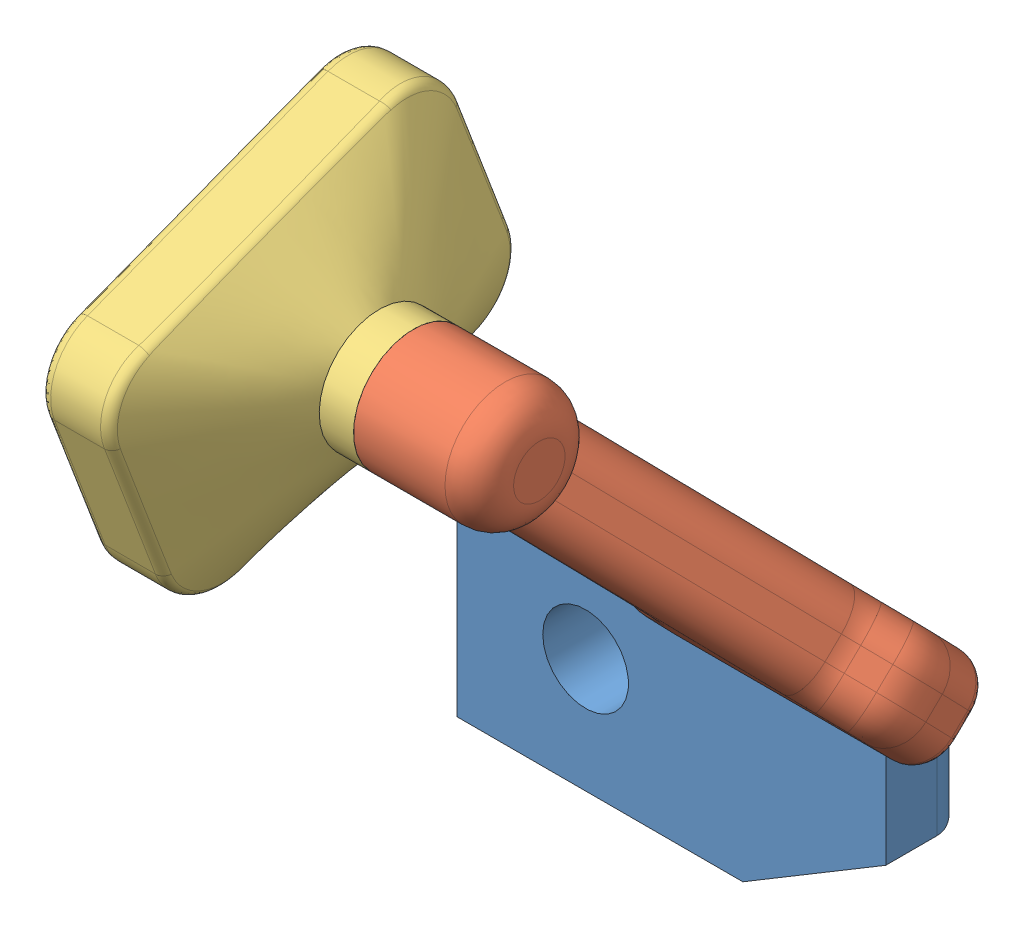
SolidWorks assembly ens, configuration Default. Lengths in mm.
Overall size (8.8 12.26 10.33).
3 component instances, 3 part files, 4 mates.
Components (placement in the parent):
- parte1-1: parte1 [Default] at origin size (7.5 4 1.4)
- parte2-1: parte2 [Default] at (1.55 2.1493 1.2671) x (1 0 0) z (0 -0.695166 0.71885) size (5 9.3 2.1)
- parte3-1: parte3 [Default] at (-0.25 7.0016 5.9594) x (1 0 0) z (0 -0.355335 0.934739) size (3 4.5 6.5)
Mates (geometry in assembly coordinates):
- Coincident1: coincident: plane of parte1-1 through (5.25 -0.5 1.4) normal (1 0 0); plane of parte2-1 through (5.25 1.7322 1.6984) normal (1 0 0)
- Concentric1: concentric: cylinder of parte1-1 through (5.25 1.5 0.5) axis (-1 0 0) radius 0.5; cylinder of parte2-1 through (1.85 1.5 0.5) axis (1 0 0) radius 0.5
- Concentric2: concentric: circle of parte2-1; circle of parte3-1
- Coincident3: coincident: plane of parte2-1 through (1.55 7.0016 5.9594) normal (-1 0 0); plane of parte3-1 through (1.55 7.0016 5.9594) normal (1 0 0)
